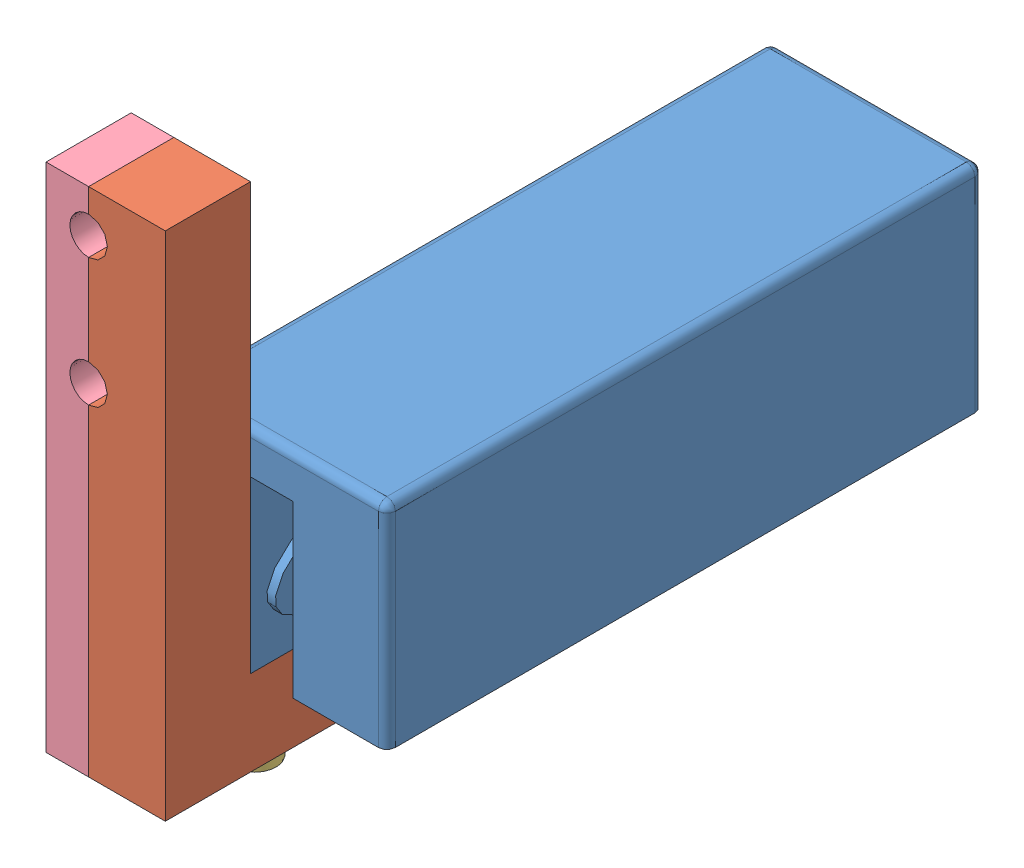
SolidWorks assembly bremse links, configuration Standard. Lengths in mm.
Overall size (30 63 80).
5 component instances, 4 part files, 9 mates.
Components (placement in the parent):
- bremsklotz-links-1: bremsklotz-links [Standard] at (14.7584 -12.9802 0) size (25 25 70)
- winkel-1: winkel [Standard] at (-21.36 -20.4697 44.8997) x (1 0 0) z (0 -1 0) size (9 45 60)
- 10_M3_imbus-1: 10_M3_imbus [Standard] at (-20.9509 -10.4697 40.077) x (-0.837169 0 -0.546944) z (-0.546944 0 0.837169) size (5 13 5)
- 10_M3_imbus-2: 10_M3_imbus [Standard] at (-20.9509 -10.4697 65.077) x (-0.837169 0 -0.546944) z (-0.546944 0 0.837169) size (5 13 5)
- winkelzusatz-1: winkelzusatz [Standard] at (-19.1911 39.5303 74.3153) x (1 0 0) z (0 -1 0) size (5 10 60)
Mates (geometry in assembly coordinates):
- Deckungsgleich28: coincident anti-aligned: plane of bremsklotz-links-1 through (-17.1604 -10.4697 70) normal (0 -1 0); plane of winkel-1 through (-17.1604 -10.4697 35) normal (0 1 0)
- Deckungsgleich29: coincident aligned: axis of bremsklotz-links-1; axis of winkel-1
- Deckungsgleich30: coincident aligned: axis of bremsklotz-links-1; axis of winkel-1
- Konzentrisch1: concentric aligned: circle of winkel-1 centre (-12.6604 -20.4697 40) axis (0 -1 0); circle of 10_M3_imbus-1 centre (-12.6604 -20.4697 40) axis (0 -1 0)
- Konzentrisch2: concentric aligned: circle of winkel-1 centre (-12.6604 -20.4697 65) axis (0 -1 0); circle of 10_M3_imbus-2 centre (-12.6604 -20.4697 65) axis (0 -1 0)
- Deckungsgleich31: coincident anti-aligned: plane of winkel-1 through (-17.1604 -20.4697 35) normal (0 -1 0); plane of 10_M3_imbus-2 through (-12.6604 -20.4697 65) normal (0 1 0)
- Deckungsgleich32: coincident aligned: plane of winkel-1 through (-17.1604 -20.4697 35) normal (0 -1 0); circle of 10_M3_imbus-1 centre (-12.6604 -20.4697 40) axis (0 -1 0)
- Deckungsgleich33: coincident anti-aligned: line of winkel-1; line of winkelzusatz-1
- Deckungsgleich34: coincident anti-aligned: unknown of winkel-1; unknown of winkelzusatz-1
